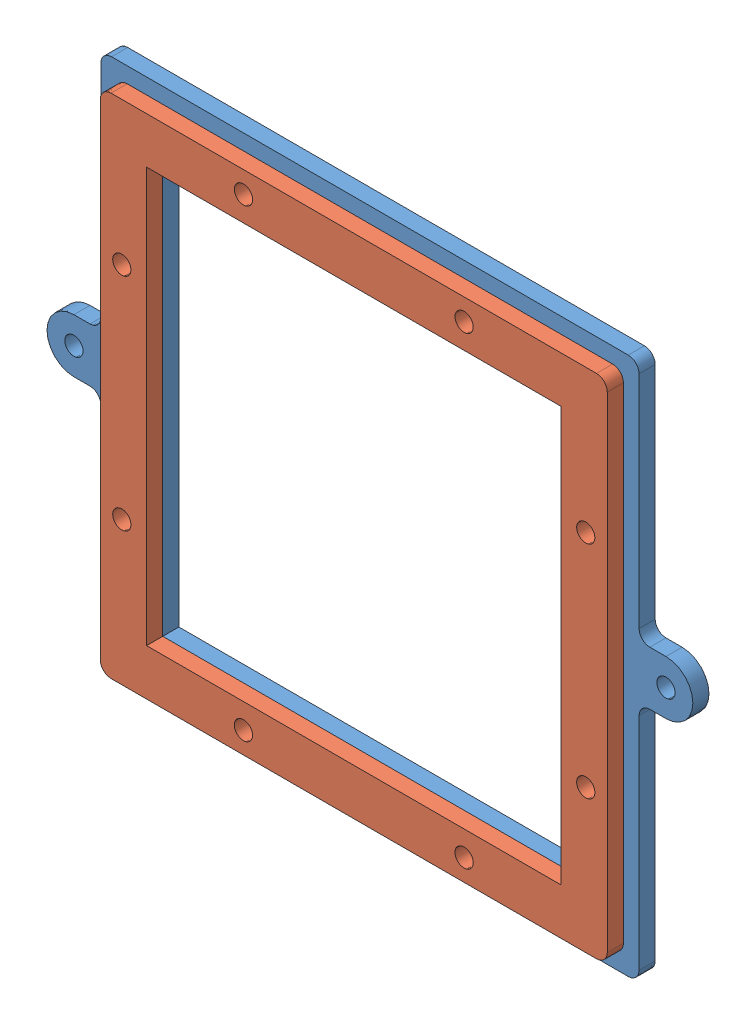
SolidWorks assembly 隔热玻璃架, configuration 默认. Lengths in mm.
Overall size (120 100 6).
2 component instances, 2 part files, 4 mates.
Components (placement in the parent):
- 零件1^隔热玻璃架-1: 零件1^隔热玻璃架 [默认] at origin size (120 100 3) (virtual)
- 零件2^隔热玻璃架-1: 零件2^隔热玻璃架 [默认] at (0 0 3) size (94.2 94.2 3) (virtual)
Mates (geometry in assembly coordinates):
- 在位1: in place: plane of 零件1^隔热玻璃架-1 through (0 0 3) normal (0 0 1); plane of 零件2^隔热玻璃架-1 through (0 0 3) normal (0 0 1); moOrthogonalPlaneRef_w of 零件1^隔热玻璃架-1 through (0 0 3) normal (0 0 1); plane of 零件2^隔热玻璃架-1 through (0 0 3) normal (0 1 0); plane of 零件1^隔热玻璃架-1 through (0 0 3) normal (0 0 1); plane of 零件2^隔热玻璃架-1 through (0 0 3) normal (1 0 0); plane of 零件1^隔热玻璃架-1 through (0 0 3) normal (0 0 1); unknown of 零件2^隔热玻璃架-1
- 重合1: coincident: plane of 零件1^隔热玻璃架-1; plane of 零件2^隔热玻璃架-1
- 重合2: coincident: moOrthogonalPlaneRef_w of 零件1^隔热玻璃架-1 through (0 0 3) normal (0 1 0); plane of 零件2^隔热玻璃架-1 through (0 0 3) normal (0 1 0)
- 重合3: coincident: moOrthogonalPlaneRef_w of 零件1^隔热玻璃架-1 through (0 0 3) normal (-1 0 0); plane of 零件2^隔热玻璃架-1 through (0 0 3) normal (1 0 0)
